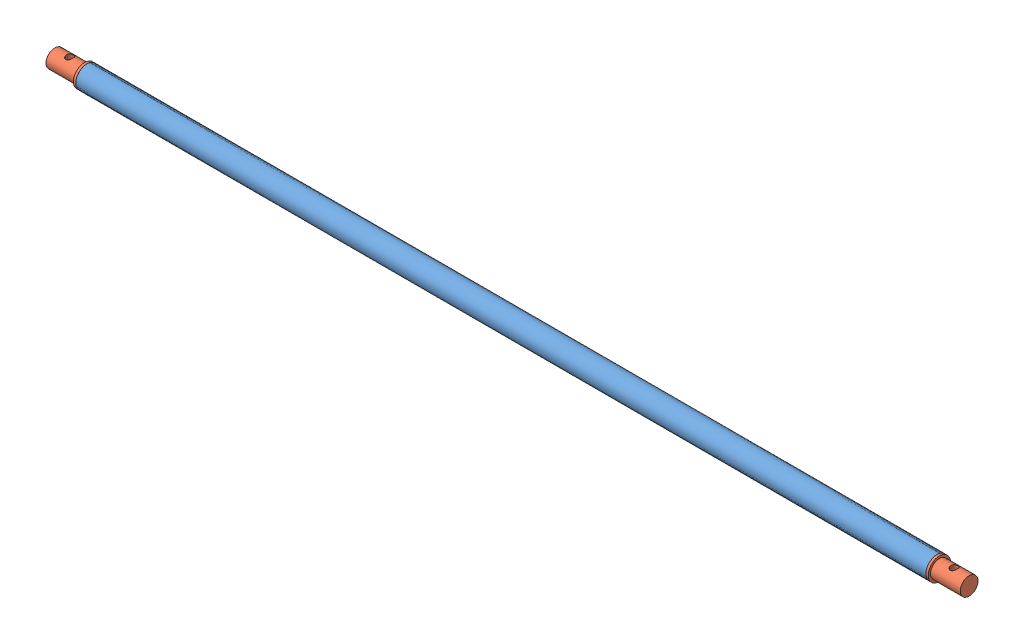
SolidWorks assembly LAS-01-0014, configuration Default. Lengths in mm.
Overall size (491.74 11.99 11.99).
3 component instances, 2 part files, 3 mates.
Components (placement in the parent):
- LAS-01-0012-1: LAS-01-0012 [Default] at (393.0152 13.8281 52.6814) x (0 -1 0) z (-1 0 0) size (11.99 11.99 457.2)
- LAS-01-0010-1: LAS-01-0010 [Default] at (-64.5648 13.8281 52.6814) size (33.78 11.99 11.99)
- LAS-01-0010-2: LAS-01-0010 [Default] at (393.3952 13.8281 52.6814) x (-1 0 0) z (0 0 -1) size (33.78 11.99 11.99)
Mates (geometry in assembly coordinates):
- ProfileCenter1: profile center aligned: circle of LAS-01-0010-1; circle of LAS-01-0012-1
- ProfileCenter2: profile center anti-aligned: circle of LAS-01-0010-2; circle of LAS-01-0012-1
- Coincident2: coincident aligned: plane of LAS-01-0010-1 through (-64.5648 13.8281 52.6814) normal (0 1 0); plane of LAS-01-0010-2 through (393.3952 13.8281 52.6814) normal (0 1 0)
